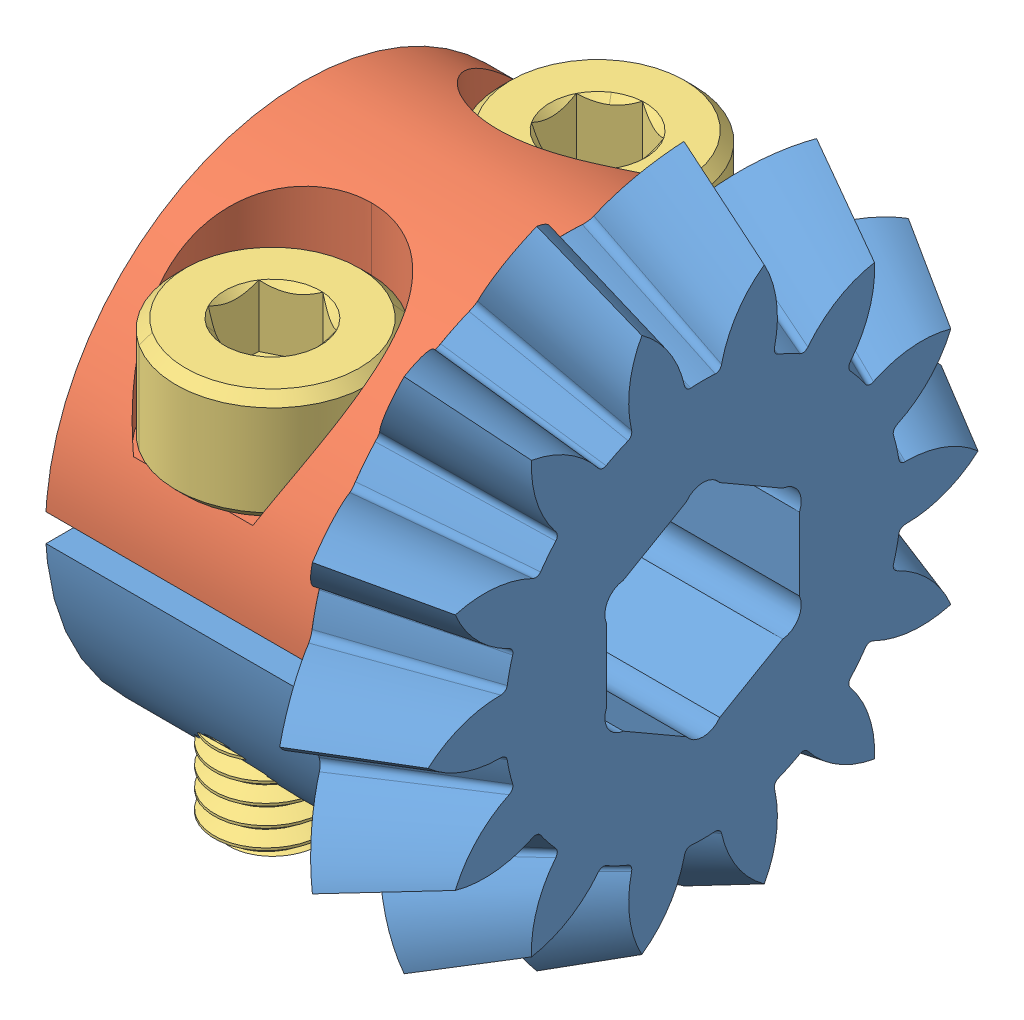
SolidWorks assembly 2306-4008-0014 small 2 to 1 bevel gear, configuration Default. Lengths in mm.
Overall size (15.4 23.91 24.42).
4 component instances, 3 part files, 0 mates.
Components (placement in the parent):
- 2306-4008-0014.STEP-1: 2306-4008-0014.STEP [Default] at (-4.2928 -28.4802 22.5212) size (15.33 23.91 24.42)
- 2306-4008-0014 clamp.STEP-1: 2306-4008-0014 clamp.STEP [Default] at (-4.2932 -28.4802 22.5212) size (9.55 8.86 18.69)
- 2800-0004-0012_90128A207.STEP-1: 2800-0004-0012_90128A207.STEP [Default] at (-8.9015 -37.2302 16.6212) x (0.549526 0 0.835476) z (0 -1 0) size (7 7 16.01)
- 2800-0004-0012_90128A207.STEP-2: 2800-0004-0012_90128A207.STEP [Default] at (-8.9015 -37.2302 28.4212) x (0.549526 0 -0.835476) z (0 -1 0) size (7 7 16.01)
